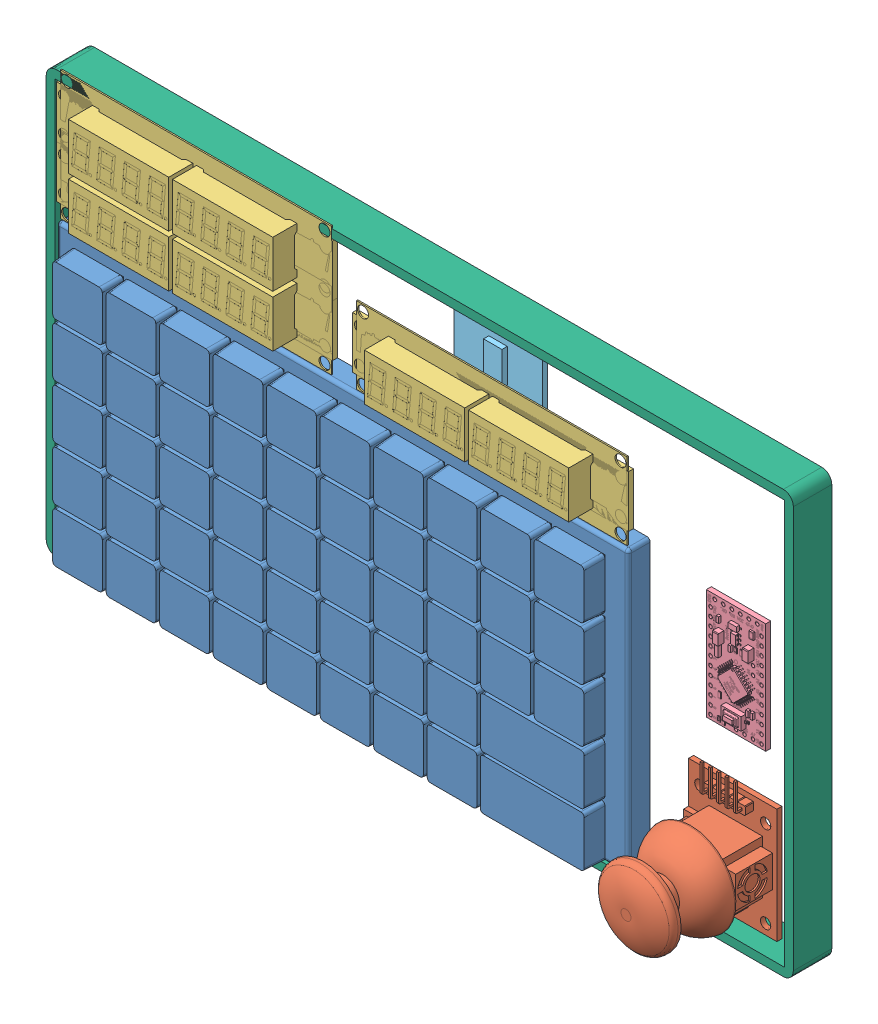
SolidWorks assembly Keypad_48_keys, configuration  . Lengths in mm.
Overall size (223.43 126.75 39.35).
9 component instances, 7 part files, 22 mates.
Components (placement in the parent):
- keypad_8x6_48_keys-1: keypad_8x6_48_keys [ ] at (0 42 5) size (196.6 109.6 14.5)
- Joystick-1: Joystick [ ] at (124.9 34.3 5) x (-1 0 0) z (0 1 0) size (27.65 36.85 39.55)
- 2xLED7seg_max7219-1: 2xLED7seg_max7219 [ ] at (-3.356 85.155 11.0885) x (-1 0 0) z (0 0 -1) size (82.5 23 10.41)
- 2xLED7seg_max7219-2: 2xLED7seg_max7219 [ ] at (85.144 85.155 11.0885) x (-1 0 0) z (0 0 -1) size (82.5 23 10.41)
- 2xLED7seg_max7219-3: 2xLED7seg_max7219 [ ] at (-3.356 100.655 11.0885) x (-1 0 0) z (0 0 -1) size (82.5 23 10.41)
- Pro-Mini-1: Pro-Mini [ ] at (112.6758 64.1161 6.5) x (0 1 0) z (0 0 -1) size (33.02 17.78 4.1)
- MCP2317-1: MCP2317 [ ] at (41.6275 108.9508 5) x (-1 0 0) z (0 0 1) size (26.5 21 3.2)
- 4xLEDMatrix_max7219-1: 4xLEDMatrix_max7219 [ ] at (-21.4436 150.9205 8.6408) size (129.5 32 13) (hidden)
- box^Keypad_48_keys-1: box^Keypad_48_keys [ ] at origin size (223.43 126.2 11.5) (virtual)
Mates (geometry in assembly coordinates):
- Совпадение1: coincident: plane of keypad_8x6_48_keys-1 through (0 42 5) normal (0 0 -1); plane of 2xLED7seg_max7219-1 through (-3.356 94.6772 5) normal (0 0 -1)
- Совпадение2: coincident: plane of keypad_8x6_48_keys-1 through (0 42 5) normal (0 0 -1); plane of Joystick-1 through (124.9 34.3 5) normal (0 0 -1)
- Расстояние1: distance = 5 mm: plane of assembly through (0 0 0) normal (0 0 1); plane of keypad_8x6_48_keys-1 through (0 42 5) normal (0 0 -1)
- Симметричный1: symmetric: plane of keypad_8x6_48_keys-1 through (-85.5 84 11.5) normal (-1 0 0); plane of keypad_8x6_48_keys-1 through (85.5 84 11.5) normal (1 0 0); plane of assembly
- Совпадение3: coincident: plane of keypad_8x6_48_keys-1 through (-85.5 0 11.5) normal (0 -1 0); plane of assembly through (0 0 0) normal (0 1 0)
- Совпадение4: coincident: plane of 2xLED7seg_max7219-1 through (-43.6289 89.75 18.7) normal (0 -1 0); plane of 2xLED7seg_max7219-2 through (13.7561 89.75 18.7) normal (0 -1 0)
- Совпадение5: coincident: plane of 2xLED7seg_max7219-1 through (-3.356 85.155 10) normal (0 0 -1); plane of 2xLED7seg_max7219-2 through (85.144 85.155 10) normal (0 0 -1)
- Совпадение6: coincident: plane of 2xLED7seg_max7219-1 through (-3.356 85.155 10) normal (0 0 -1); plane of 2xLED7seg_max7219-3 through (-3.356 100.655 10) normal (0 0 -1)
- Совпадение7: coincident: plane of 2xLED7seg_max7219-1 through (-3 104.5 10) normal (0 1 0); plane of 2xLED7seg_max7219-3 through (-3 104.5 10) normal (0 -1 0)
- Совпадение8: coincident: plane of 2xLED7seg_max7219-1 through (-85.5 104.5 10) normal (-1 0 0); plane of 2xLED7seg_max7219-3 through (-85.5 120 10) normal (-1 0 0)
- Совпадение9: coincident: plane of keypad_8x6_48_keys-1 through (-85.5 84 11.5) normal (-1 0 0); plane of 2xLED7seg_max7219-1 through (-85.5 104.5 10) normal (-1 0 0)
- Совпадение10: coincident: plane of keypad_8x6_48_keys-1 through (85.5 84 11.5) normal (1 0 0); plane of 2xLED7seg_max7219-2 through (85.5 104.5 10) normal (1 0 0)
- Совпадение11: coincident: plane of keypad_8x6_48_keys-1 through (0 42 5) normal (0 0 -1); plane of Pro-Mini-1 through (112.6758 64.1161 5) normal (0 0 -1)
- Совпадение13: coincident: plane of keypad_8x6_48_keys-1 through (-85.5 0 11.5) normal (0 -1 0); plane of Joystick-1 through (124.9 0 6.5) normal (0 -1 0)
- Расстояние2: distance = 13 mm: plane of Joystick-1 through (98.5 34.3 6.5) normal (-1 0 0); plane of keypad_8x6_48_keys-1 through (85.5 84 11.5) normal (1 0 0)
- Расстояние3: distance = 5 mm: plane of 2xLED7seg_max7219-1 through (-3 89 10) normal (0 -1 0); plane of keypad_8x6_48_keys-1 through (-85.5 84 11.5) normal (0 1 0)
- Расстояние4: distance = 5 mm: plane of 2xLED7seg_max7219-1 through (-3.356 85.155 10) normal (0 0 -1); plane of keypad_8x6_48_keys-1 through (0 42 5) normal (0 0 -1)
- Совпадение14: coincident: plane of keypad_8x6_48_keys-1 through (0 42 5) normal (0 0 -1); plane of MCP2317-1 through (41.6275 108.9508 5) normal (0 0 -1)
- На месте1: in place: plane of box^Keypad_48_keys-1 through (0 0 0) normal (0 0 1); moOrthogonalPlaneRef_w of box^Keypad_48_keys-1 through (0 0 0) normal (0 1 0); plane of box^Keypad_48_keys-1 through (0 0 0) normal (1 0 0); unknown of box^Keypad_48_keys-1
- Совпадение16: coincident: plane of box^Keypad_48_keys-1; plane of assembly
- Совпадение17: coincident: plane of box^Keypad_48_keys-1 through (0 0 0) normal (0 1 0); moOrthogonalPlaneRef_w of assembly
- Совпадение18: coincident: plane of box^Keypad_48_keys-1 through (0 0 0) normal (1 0 0); moOrthogonalPlaneRef_w of assembly
